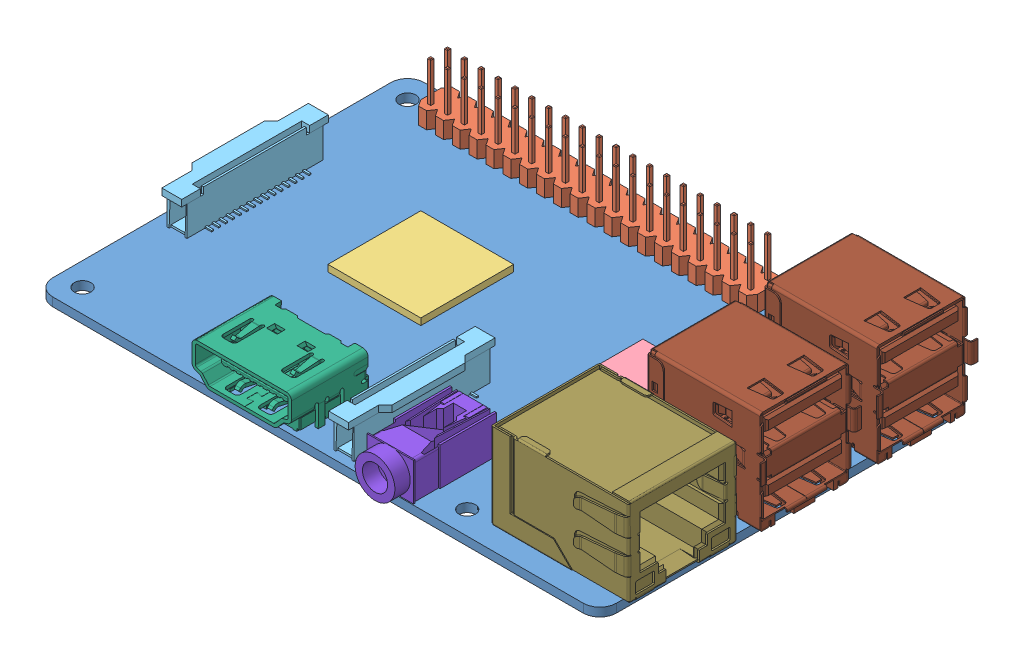
SolidWorks assembly raspi2, configuration Default. Lengths in mm.
Overall size (91.42 20.51 58.3).
14 component instances, 12 part files, 0 mates.
Components (placement in the parent):
- User Library-RaspberryPi2 STEP214_Mainboard2-1: User Library-RaspberryPi2 STEP214_Mainboard2 [Default] at origin size (85 1.3 56)
- User Library-RaspberryPi2 STEP214_GPIO-1: User Library-RaspberryPi2 STEP214_GPIO [Default] at (-11.37 0 -24.5) x (0 0 1) z (-1 0 0) size (5 11.5 50.8)
- User Library-RaspberryPi2 STEP214_Processor-1: User Library-RaspberryPi2 STEP214_Processor [Default] at (-15.5 0 -3) x (0 0 1) z (-1 0 0) size (14 1 14)
- User Library-RaspberryPi2 STEP214_GPU-1: User Library-RaspberryPi2 STEP214_GPU [Default] at (15.25 0 -5.75) x (0 0 1) z (-1 0 0) size (9.1 1 9.1)
- User Library-RaspberryPi2 STEP214_CameraAssembly-1: User Library-RaspberryPi2 STEP214_CameraAssembly [Default] at (10.0885 -2.9159 16.55) x (-1 0 0) z (0 0 -1) size (6.09 6.17 23.84)
- User Library-RaspberryPi2 STEP214_CameraAssembly-2: User Library-RaspberryPi2 STEP214_CameraAssembly [Default] at (-46.3885 -2.9159 0) size (6.09 6.17 23.84)
- User Library-RaspberryPi2 STEP214_HDMI-1: User Library-RaspberryPi2 STEP214_HDMI [Default] at (-10.2 0.27 29.3) size (15 8.38 12.15)
- User Library-RaspberryPi2 STEP214_RAM-1: User Library-RaspberryPi2 STEP214_RAM [Default] at (0.5 -2.3 -6) x (0 0 1) z (-1 0 0) size (12 1 12)
- User Library-RaspberryPi2 STEP214_Audio-1: User Library-RaspberryPi2 STEP214_Audio [Default] at (10.9 0.15 21.75) size (7 6 14.8)
- User Library-RaspberryPi2 STEP214_MicroSDSocket-1: User Library-RaspberryPi2 STEP214_MicroSDSocket [Default] at (-34.5 -1.3 -0.7) x (0 0 -1) z (-1 0 0) size (13 1.3 14)
- User Library-RaspberryPi2 STEP214_MicroSD-1: User Library-RaspberryPi2 STEP214_MicroSD [Default] at (-37 -2.3 0.1) x (0 0 1) z (-1 0 0) size (11.29 1 15)
- User Library-RaspberryPi2 STEP214_usb double-1: User Library-RaspberryPi2 STEP214_usb double [Default] at (30.38 -0.09 -18.85) x (0 0 -1) z (1 0 0) size (15.6 18.75 17.92)
- User Library-RaspberryPi2 STEP214_usb double-2: User Library-RaspberryPi2 STEP214_usb double [Default] at (30.38 -0.09 -1.25) x (0 0 -1) z (1 0 0) size (15.6 18.75 17.92)
- User Library-RaspberryPi2 STEP214_RJ45-LED-1: User Library-RaspberryPi2 STEP214_RJ45-LED [Default] at (34.11 7.4 17.348) x (1 0 0) z (0 -1 0) size (23.41 18.34 17.45)
